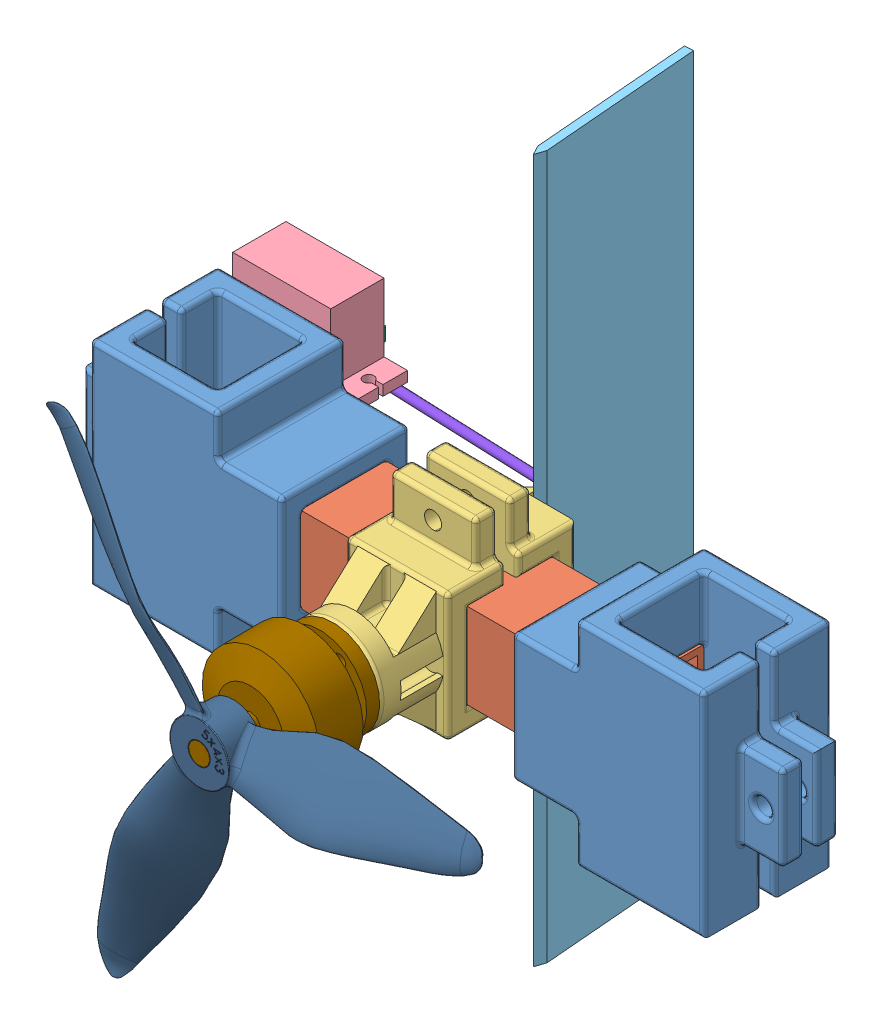
SolidWorks assembly rear motor, configuration Default. Lengths in mm.
Overall size (382 520 366.95).
23 component instances, 17 part files, 65 mates.
Components (placement in the parent):
- Tail Boom-1: Tail Boom [Default] at (20.2266 -517.2222 1.0272) size (20 1000 20) (hidden)
- Tail holder 1-1: Tail holder 1 [Default] at (31.2437 406.7778 -2.2179) x (1 0 0) z (0 -1 0) size (40 30 124) (hidden)
- tail holder 2-2: tail holder 2 [Default] at (21.0079 496.8403 300.9572) x (0 1 0) z (-1 0 0) size (10 323.08 10) (hidden)
- Tail Boom-2: Tail Boom [Default] at (-93.7734 -517.2222 1.0272) x (-1 0 0) z (0 0 -1) size (20 1000 20) (hidden)
- Tail holder 1-3: Tail holder 1 [Default] at (-104.7904 406.7778 4.2723) x (-1 0 0) z (0 -1 0) size (40 30 124) (hidden)
- Vertical Stabilizer mk1-1: Vertical Stabilizer mk1 [Default] at (20.2266 346.1726 11.0272) x (-1 0 0) z (0 0 1) size (32.74 289.69 300.05) (hidden)
- tail holder 2-3: tail holder 2 [Default] at (-90.2109 492.4966 300.9572) x (1 0 0) z (0 1 0) size (10 323.08 10) (hidden)
- Vertical Stabilizer mk1-2: Vertical Stabilizer mk1 [Default] at (-93.7734 346.1726 11.0272) x (-1 0 0) z (0 0 1) size (32.74 289.69 300.05) (hidden)
- Horisontal stabiliser 11-1: Horisontal stabiliser 11 [Default] at (-336.7734 468.2778 304.1044) x (0 1 0) z (1 0 0) size (201.07 42.21 600) (hidden)
- top tail holder-1: top tail holder [Default] at (-94.9301 489.7185 257.1044) x (0 -1 0) z (-1 0 0) size (36 23 14) (hidden)
- top tail holder-3: top tail holder [Default] at (19.0699 489.7185 257.1044) x (0 -1 0) z (-1 0 0) size (36 23 14) (hidden)
- Horizontal stabilizer bar-1: Horizontal stabilizer bar [Default] at (-336.7734 503.5632 301.2248) x (0 0 -1) z (1 0 0) size (10 10 600) (hidden)
- Tail motor mount A mk1-1: Tail motor mount A mk1 [Default] at (-97.9309 255.7778 2.925) x (1 0 0) z (0 -1 0) size (55 30 50)
- Tail motor mount A mk1-2: Tail motor mount A mk1 [Default] at (24.3842 255.7778 -0.8707) x (-1 0 0) z (0 -1 0) size (55 30 50)
- Rear motor crossbar-1: Rear motor crossbar [Default] at (-83.7734 228.9438 2.5044) x (0 1 0) z (1 0 0) size (20 20 94)
- Tail motor mount B mk1-1: Tail motor mount B mk1 [Default] at (-38.3549 230.7778 31.0272) x (-1 0 0) z (0 -1 0) size (24 47 40)
- Servo mk1-1: Servo mk1 [Default] at (-101.0589 247.0979 -13.9728) x (0.971449 -0.237248 0) z (0.237248 0.971449 0) size (33.6 12.5 34.08)
- Flap mk1-1: Flap mk1 [Default] at (-35.9741 313.2778 -18.4266) x (0.996557 0 -0.082916) z (0 -1 0) size (2 40 165)
- Servo arm mk1-1: Servo arm mk1 [Default] at (-114.6733 232.8778 17.976) x (-0.995872 0 0.090763) z (0 -1 0) size (10.8 29.4 3.1)
- Servo hook mk1-1: Servo hook mk1 [Default] at (-40.7562 235.7778 -42.4932) x (-0.996557 0 0.082916) z (0.082916 0 0.996557) size (6 10 10)
- Servo wire-1: Servo wire [Default] at (-102.5419 227.3778 -25.7684) x (-0.039777 0 0.999209) z (0 1 0) size (2 59.28 13)
- Tail motor-1: Tail motor [Default] at (-36.7734 230.7778 31.0272) x (-0.55385 -0.832617 0) z (0 0 -1) size (27.5 27.5 31.35)
- tail prop-1: tail prop [Default] at (-36.7734 230.7778 54.3772) x (0.926424 -0.376482 0) z (-0.376482 -0.926424 0) size (111.23 11.43 97.73)
Mates (geometry in assembly coordinates):
- Distance4: distance = 94 mm anti-aligned: plane of Tail Boom-1 through (10.2266 482.7778 10.0272) normal (-1 0 0); plane of Tail Boom-2 through (-83.7734 482.7778 -7.9728) normal (1 0 0)
- Coincident27: coincident aligned: plane of Tail Boom-1 through (11.2266 482.7778 -8.9728) normal (0 0 -1); plane of Tail Boom-2 through (-84.7734 482.7778 -8.9728) normal (0 0 -1)
- Coincident59: coincident anti-aligned: plane of Tail Boom-2 through (-84.7734 482.7778 -8.9728) normal (0 0 -1); plane of Tail holder 1-3 through (-104.7904 381.7778 -8.9728) normal (0 0 1)
- Coincident60: coincident anti-aligned: plane of Tail Boom-2 through (-103.7734 482.7778 -7.9728) normal (-1 0 0); plane of Tail holder 1-3 through (-103.7734 381.7778 4.2723) normal (1 0 0)
- Parallel1: parallel anti-aligned: plane of Tail Boom-2 through (-83.7734 482.7778 -7.9728) normal (1 0 0); plane of Tail holder 1-3 through (-83.7734 381.7778 4.2723) normal (-1 0 0)
- Coincident63: coincident anti-aligned: plane of Tail Boom-2 through (-84.7734 482.7778 -7.9728) normal (0 1 0); plane of Tail holder 1-3 through (-104.7904 482.7778 4.2723) normal (0 -1 0)
- Coincident64: coincident anti-aligned: plane of Tail Boom-1 through (11.2266 482.7778 10.0272) normal (0 1 0); plane of Tail holder 1-1 through (31.2437 482.7778 -2.2179) normal (0 -1 0)
- Coincident65: coincident anti-aligned: plane of Tail Boom-1 through (10.2266 482.7778 10.0272) normal (-1 0 0); plane of Tail holder 1-1 through (10.2266 381.7778 -2.2179) normal (1 0 0)
- Coincident66: coincident anti-aligned: plane of Tail Boom-1 through (11.2266 482.7778 11.0272) normal (0 0 1); plane of Tail holder 1-1 through (31.2437 381.7778 11.0272) normal (0 0 -1)
- Coincident67: coincident anti-aligned: plane of Tail holder 1-1 through (31.2437 498.2778 110.0272) normal (0 -1 0); plane of tail holder 2-2 through (25.2266 498.2778 -9.0428) normal (0 1 0)
- Coincident68: coincident aligned: plane of Tail holder 1-1 through (31.2437 381.7778 -13.9728) normal (0 0 -1); plane of tail holder 2-2 through (16.2266 489.2778 -13.9728) normal (0 0 -1)
- Coincident69: coincident anti-aligned: plane of Tail holder 1-1 through (15.2266 406.7778 110.0272) normal (1 0 0); plane of tail holder 2-2 through (15.2266 488.2778 -9.0428) normal (-1 0 0)
- Coincident71: coincident aligned: plane of Tail holder 1-3 through (-104.7904 381.7778 -13.9728) normal (0 0 -1); plane of tail holder 2-3 through (-97.7734 497.2778 -13.9728) normal (0 0 -1)
- Coincident72: coincident anti-aligned: plane of Tail holder 1-3 through (-88.7734 406.7778 -107.9728) normal (-1 0 0); plane of tail holder 2-3 through (-88.7734 488.2778 -9.0428) normal (1 0 0)
- Coincident73: coincident anti-aligned: plane of Horisontal stabiliser 11-1 through (-336.7734 486.2778 267.1044) normal (0 1 0); plane of top tail holder-3 through (27.2266 486.2778 297.1044) normal (0 -1 0)
- Coincident74: coincident anti-aligned: plane of Horisontal stabiliser 11-1 through (27.2266 468.2778 267.1044) normal (-1 0 0); plane of top tail holder-3 through (27.2266 500.2778 297.1044) normal (1 0 0)
- Coincident75: coincident anti-aligned: plane of Horisontal stabiliser 11-1 through (-336.7734 468.2778 311.1044) normal (0 0 -1); plane of top tail holder-3 through (19.0699 489.7185 311.1044) normal (0 0 1)
- Coincident76: coincident anti-aligned: plane of Horisontal stabiliser 11-1 through (-100.7734 468.2778 267.1044) normal (1 0 0); plane of top tail holder-1 through (-100.7734 500.2778 297.1044) normal (-1 0 0)
- Coincident77: coincident anti-aligned: plane of Horisontal stabiliser 11-1 through (-336.7734 486.2778 267.1044) normal (0 1 0); plane of top tail holder-1 through (-86.7734 486.2778 297.1044) normal (0 -1 0)
- Coincident78: coincident anti-aligned: plane of Horisontal stabiliser 11-1 through (-336.7734 468.2778 311.1044) normal (0 0 -1); plane of top tail holder-1 through (-94.9301 489.7185 311.1044) normal (0 0 1)
- Coincident81: coincident anti-aligned: plane of Horisontal stabiliser 11-1 through (-390.7734 500.2778 304.1044) normal (0 1 0); plane of Horizontal stabilizer bar-1 through (263.2266 500.2778 309.1044) normal (0 -1 0)
- Coincident83: coincident anti-aligned: plane of Horisontal stabiliser 11-1 through (-390.7734 468.2778 309.1044) normal (0 0 -1); plane of Horizontal stabilizer bar-1 through (263.2266 510.2778 309.1044) normal (0 0 1)
- Coincident84: coincident aligned: plane of Horisontal stabiliser 11-1 through (263.2266 468.2778 304.1044) normal (1 0 0); plane of Horizontal stabilizer bar-1 through (263.2266 503.5632 301.2248) normal (1 0 0)
- Coincident86: coincident anti-aligned: plane of tail holder 2-3 through (-88.7734 488.2778 -9.0428) normal (1 0 0); plane of Vertical Stabilizer mk1-2 through (-88.7734 346.1726 321.0272) normal (-1 0 0)
- Coincident87: coincident anti-aligned: plane of tail holder 2-3 through (-98.7734 488.2778 -9.0428) normal (0 -1 0); plane of Vertical Stabilizer mk1-2 through (-93.7734 488.2778 321.0272) normal (0 1 0)
- Coincident89: coincident anti-aligned: plane of tail holder 2-2 through (25.2266 488.2778 -9.0428) normal (0 -1 0); plane of Vertical stabiliser 11-1 through (20.2266 488.2778 321.0272) normal (0 1 0)
- Coincident90: coincident anti-aligned: plane of tail holder 2-2 through (15.2266 488.2778 -9.0428) normal (-1 0 0); plane of Vertical stabiliser 11-1 through (15.2266 346.1726 321.0272) normal (1 0 0)
- Coincident91: coincident anti-aligned: plane of tail holder 2-2 through (25.2266 488.2778 -9.0428) normal (1 0 0); plane of top tail holder-3 through (25.2266 489.7185 257.1044) normal (-1 0 0)
- Coincident92: coincident anti-aligned: plane of tail holder 2-2 through (25.2266 488.2778 -9.0428) normal (0 -1 0); plane of top tail holder-3 through (19.0699 488.2778 257.1044) normal (0 1 0)
- Distance5: distance = 311.0772 mm: line of top tail holder-1 through (-87.7734 500.2778 297.1044) axis (-1 0 0); plane of tail holder 2-3 through (-97.7734 497.2778 -13.9728) normal (0 0 -1)
- Coincident93: coincident anti-aligned: plane of Tail Boom-1 through (11.2266 482.7778 11.0272) normal (0 0 1); plane of Vertical stabiliser 11-1 through (20.2266 346.1726 11.0272) normal (0 0 -1)
- Coincident94: coincident anti-aligned: plane of Tail Boom-2 through (-84.7734 482.7778 11.0272) normal (0 0 1); plane of Vertical Stabilizer mk1-2 through (-93.7734 346.1726 11.0272) normal (0 0 -1)
- Coincident95: coincident anti-aligned: plane of Tail Boom-2 through (-84.7734 482.7778 -8.9728) normal (0 0 -1); plane of Tail motor mount A mk1-1 through (-103.7734 205.7778 -8.9728) normal (0 0 1)
- Coincident96: coincident anti-aligned: plane of Tail Boom-2 through (-103.7734 482.7778 -7.9728) normal (-1 0 0); plane of Tail motor mount A mk1-1 through (-103.7734 205.7778 11.0272) normal (1 0 0)
- Distance6: distance = 126 mm anti-aligned: plane of Tail holder 1-3 through (-104.7904 381.7778 4.2723) normal (0 -1 0); plane of Tail motor mount A mk1-1 through (-97.9309 255.7778 2.925) normal (0 1 0)
- Coincident98: coincident anti-aligned: plane of Tail Boom-1 through (10.2266 482.7778 10.0272) normal (-1 0 0); plane of Tail motor mount A mk1-2 through (10.2266 205.7778 -8.9728) normal (1 0 0)
- Coincident99: coincident anti-aligned: plane of Tail Boom-1 through (11.2266 482.7778 -8.9728) normal (0 0 -1); plane of Tail motor mount A mk1-2 through (30.2266 205.7778 -8.9728) normal (0 0 1)
- Distance7: distance = 126 mm anti-aligned: plane of Tail holder 1-1 through (31.2437 381.7778 -2.2179) normal (0 -1 0); plane of Tail motor mount A mk1-2 through (24.3842 255.7778 -0.8707) normal (0 1 0)
- Coincident101: coincident anti-aligned: plane of Tail motor mount A mk1-1 through (-103.7734 205.7778 -8.9728) normal (0 0 1); plane of Rear motor crossbar-1 through (10.2266 220.7778 -8.9728) normal (0 0 -1)
- Coincident102: coincident anti-aligned: plane of Tail motor mount A mk1-1 through (-48.7734 240.7778 11.0272) normal (0 -1 0); plane of Rear motor crossbar-1 through (10.2266 240.7778 11.0272) normal (0 1 0)
- Coincident103: coincident anti-aligned: plane of Tail Boom-1 through (10.2266 482.7778 10.0272) normal (-1 0 0); plane of Rear motor crossbar-1 through (10.2266 228.9438 2.5044) normal (1 0 0)
- Coincident104: coincident anti-aligned: plane of Rear motor crossbar-1 through (10.2266 220.7778 -8.9728) normal (0 0 -1); plane of Tail motor mount B mk1-1 through (-9.7734 230.7778 -8.9728) normal (0 0 1)
- Coincident105: coincident anti-aligned: plane of Rear motor crossbar-1 through (10.2266 240.7778 11.0272) normal (0 1 0); plane of Tail motor mount B mk1-1 through (-9.7734 240.7778 31.0272) normal (0 -1 0)
- Distance8: distance = 15 mm anti-aligned: plane of Tail motor mount B mk1-1 through (-48.7734 230.7778 31.0272) normal (-1 0 0); plane of Tail motor mount A mk1-1 through (-63.7734 255.7778 2.925) normal (1 0 0)
- Width2: width anti-aligned: plane of Tail motor mount B mk1-1 through (-38.3549 215.7778 11.0272) normal (0 -1 0); plane of Tail motor mount B mk1-1 through (-38.3549 245.7778 11.0272) normal (0 1 0); plane of Flap mk1-1 through (-35.9741 313.2778 -18.4266) normal (0 1 0); plane of Flap mk1-1 through (-35.9741 148.2778 -18.4266) normal (0 -1 0)
- Coincident109: coincident anti-aligned: line of Tail motor mount B mk1-1 through (-36.7734 215.7778 -15.9728) axis (0 1 0); line of Flap mk1-1 through (-36.7734 313.2778 -15.9728) axis (0 -1 0)
- LimitAngle1: limit planar angle = 1.487785 rad anti-aligned: plane of Flap mk1-1 through (-37.7699 148.2778 -15.8899) normal (-0.996557 0 0.082916); plane of Tail motor mount B mk1-1 through (-9.7734 215.7778 -13.9728) normal (0 0 -1)
- Coincident111: coincident anti-aligned: plane of Tail motor mount A mk1-1 through (-108.7734 205.7778 -13.9728) normal (0 0 -1); plane of Servo mk1-1 through (-101.0589 247.0979 -13.9728) normal (0 0 1)
- Width3: width anti-aligned: plane of Servo mk1-1 through (-105.2734 260.1778 -26.4728) normal (-1 0 0); plane of Servo mk1-1 through (-82.2734 260.1778 -26.4728) normal (1 0 0); plane of Tail motor mount A mk1-1 through (-78.7734 205.7778 16.0272) normal (1 0 0); plane of Tail motor mount A mk1-1 through (-108.7734 205.7778 16.0272) normal (-1 0 0)
- Distance9: distance = 24 mm aligned: plane of Servo mk1-1 through (-101.0589 229.7778 -13.9728) normal (0 -1 0); plane of Tail motor mount A mk1-1 through (-97.9309 205.7778 2.925) normal (0 -1 0)
- Coincident114: coincident anti-aligned: cylinder of Servo mk1-1 through (-99.0234 229.7778 -20.2228) axis (0 1 0) radius 2.4; circle of Servo arm mk1-1
- Coincident115: coincident aligned: plane of Servo mk1-1 through (-101.0589 229.7778 -13.9728) normal (0 -1 0); plane of Servo arm mk1-1 through (-114.6733 229.7778 17.976) normal (0 -1 0)
- Coincident117: coincident anti-aligned: plane of Flap mk1-1 through (-37.7699 148.2778 -15.8899) normal (-0.996557 0 0.082916); plane of Servo hook mk1-1 through (-40.1231 225.7778 -44.1722) normal (0.996557 0 -0.082916)
- Width5: width aligned: plane of Servo hook mk1-1 through (-40.7562 225.7778 -42.4932) normal (0 -1 0); plane of Servo hook mk1-1 through (-40.7562 235.7778 -42.4932) normal (0 1 0); plane of Flap mk1-1 through (-35.9741 148.2778 -18.4266) normal (0 -1 0); plane of Flap mk1-1 through (-35.9741 313.2778 -18.4266) normal (0 1 0)
- Distance12: distance = 11.62 mm aligned: plane of Servo hook mk1-1 through (-40.1231 225.7778 -44.1722) normal (-0.082916 0 -0.996557); plane of Flap mk1-1 through (-41.0866 148.2778 -55.7522) normal (-0.082916 0 -0.996557)
- LimitAngle3: limit planar angle = 1.661685 rad anti-aligned: plane of Servo arm mk1-1 through (-120.1754 229.7778 -42.3945) normal (-0.090763 0 -0.995872); plane of Tail motor mount A mk1-1 through (-108.7734 205.7778 16.0272) normal (-1 0 0)
- Concentric2: concentric aligned: cylinder of Servo arm mk1-1 through (-100.9294 229.7778 -41.1362) axis (0 1 0) radius 1; cylinder of Servo wire-1 through (-100.9294 219.8778 -41.1362) axis (0 1 0) radius 1
- Concentric3: concentric anti-aligned: cylinder of Servo hook mk1-1 through (-43.6947 244.7778 -38.8577) axis (0 -1 0) radius 1; cylinder of Servo wire-1 through (-43.6947 168.0978 -38.8577) axis (0 1 0) radius 1
- Coincident122: coincident aligned: plane of Servo arm mk1-1 through (-114.6733 232.8778 17.976) normal (0 1 0); plane of Servo wire-1 through (-100.9294 232.8778 -41.1362) normal (0 1 0)
- Coincident123: coincident anti-aligned: plane of Tail holder 1-3 through (-104.7904 488.2778 -107.9728) normal (0 1 0); plane of tail holder 2-3 through (-98.7734 488.2778 -9.0428) normal (0 -1 0)
- Coincident125: coincident anti-aligned: plane of Tail motor mount A mk1-2 through (-24.7734 240.7778 -8.9728) normal (0 -1 0); plane of Rear motor crossbar-1 through (10.2266 240.7778 11.0272) normal (0 1 0)
- Concentric13: concentric aligned: cylinder of Tail motor mount B mk1-1 through (-36.7734 230.7778 26.0272) axis (0 0 1) radius 11; cylinder of Tail motor-1 through (-36.7734 230.7778 62.3772) axis (0 0 1) radius 13.75
- Coincident126: coincident anti-aligned: plane of Tail motor mount B mk1-1 through (-38.3549 230.7778 31.0272) normal (0 0 1); plane of Tail motor-1 through (-36.7734 230.7778 31.0272) normal (0 0 -1)
- Concentric14: concentric anti-aligned: cylinder of Tail motor-1 through (-36.7734 230.7778 62.3772) axis (0 0 1) radius 2.5; cylinder of tail prop-1 through (-36.7734 230.7778 62.3772) axis (0 0 -1) radius 2.5
- Coincident127: coincident aligned: plane of Tail motor-1 through (-38.158 228.6963 62.3772) normal (0 0 1); plane of tail prop-1 through (-36.7734 230.7778 62.3772) normal (0 0 1)
